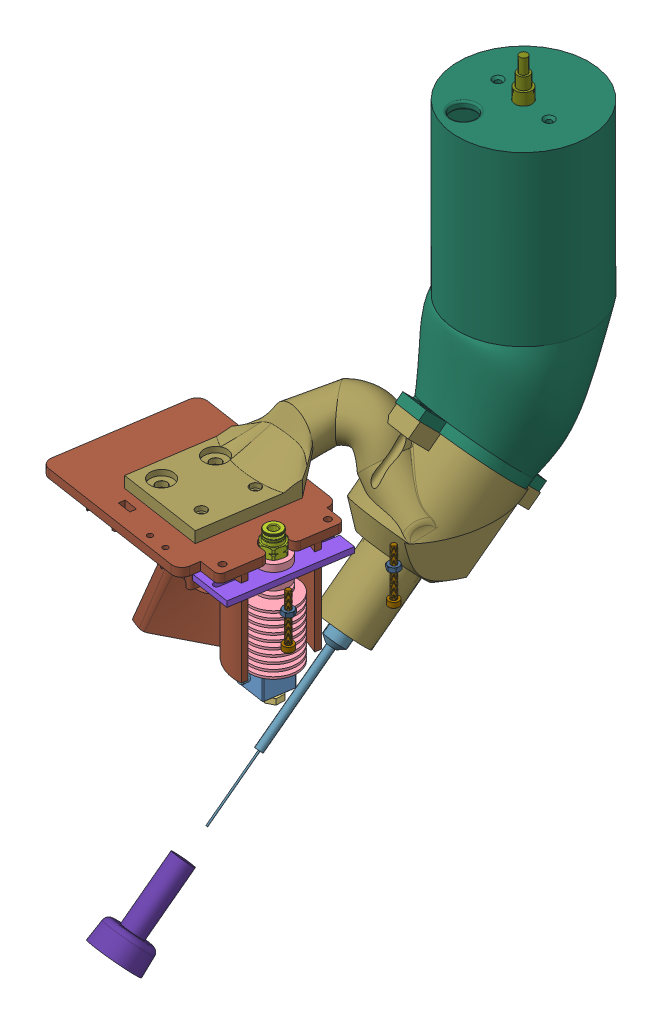
SolidWorks assembly new frame assembly, configuration Default. Lengths in mm.
Overall size (173.27 365.26 314.69).
20 component instances, 17 part files, 26 mates.
Components (placement in the parent):
- E3D-1: E3D [Default] at (19.6616 -17.5766 41.1358) x (-0.988808 0 -0.149195) z (0.149195 0 -0.988808) size (28.79 69.7 28.79)
  - E3D Heat Block-1: E3D Heat Block [Default] at origin size (16 12 16)
  - E3D Heatbreak-1: E3D Heatbreak [Default] at (-4 19.55 0) x (-0.93266 0 -0.360757) z (-0.360757 0 0.93266) size (6 25.1 6)
  - E3D Nozzle-1: E3D Nozzle [Default] at (-4 -3.5 0) x (-0.097107 0 -0.995274) z (0.995274 0 -0.097107) size (9.24 12.5 8)
  - E3D Heatsink-1: E3D Heatsink [1.75 Bowden] at (-4 39.15 0) x (0.986263 0 -0.165183) z (0.165183 0 0.986263) size (25 50.1 25)
  - cartridge heater-1: cartridge heater [Default] at (3 7 0) x (0 0 1) z (-0.150948 -0.988542 0) size (32 6.2 6.2)
  - thermistor-1: thermistor [Default] at (-6 2 6.5) x (-0.997586 0.069447 0) z (-0.069447 -0.997586 0) size (2 13.25 2)
- PB156_1_8-1: PB156_1_8 [Default] at (23.6169 46.9462 41.7325) x (0 -1 0) z (0.258692 0 0.96596) size (19.6 12.3 13.69)
- hotend bracket-1: hotend bracket [Default] at (30.0179 39.8834 73.0379) x (0.149195 0 -0.988808) z (0.988808 0 0.149195) size (60 3.04 22)
- socket head cap screw_am-14: socket head cap screw_am [B18.3.1M - 3 x 0.5 x 25 Hex SHCS -- 25SHX] at (70.4306 36.8834 24.1201) x (0 1 0) z (0 0 1) size (28 5.5 5.5)
- socket head cap screw_am-15: socket head cap screw_am [B18.3.1M - 3 x 0.5 x 25 Hex SHCS -- 25SHX] at (63.0246 36.8834 73.2045) x (0 1 0) z (-0.007083 0 0.999975) size (28 5.5 5.5)
- hex nut style 1_am-9: hex nut style 1_am [B18.2.4.1M - Hex nut, Style 1,  M3 x 0.5 --D-N] at (70.4306 55.9307 24.1201) x (1 0 0) z (0 1 0) size (5.5 6.35 2.4)
- hex nut style 1_am-10: hex nut style 1_am [B18.2.4.1M - Hex nut, Style 1,  M3 x 0.5 --D-N] at (63.0246 55.9307 73.2045) x (0.837169 0 0.546944) z (0 1 0) size (5.5 6.35 2.4)
- combined_frame-1: combined_frame [Default] at (-56.3869 -3.8922 -39.5735) x (0.988808 0 0.149195) z (-0.149195 0 0.988808) size (99.47 66.34 74.84)
- plasma_frame-1: plasma_frame [Default] at (-26.1139 51.1734 22.9932) x (-0.149195 0 0.988808) z (-0.988808 0 -0.149195) size (145.86 100.19 90.21)
- plasma_front_cone-1: plasma_front_cone [Default] at (59.1878 56.1232 -48.6716) x (-0.988808 0 -0.149195) z (-0.105497 0.707107 0.699193) size (47.33 150.21 106.88)
- needle_tip-1: needle_tip [Default] at (29.0488 10.8886 -7.4726) x (-0.903244 0.362246 0.230061) z (0.415958 0.607271 0.676906) size (11.1 112.62 11.1)
- plasma_frame_top-1: plasma_frame_top [Default] at (35.4811 55.4161 -50.1032) x (0.988808 0 0.149195) z (-0.105497 0.707107 0.699193) size (80.16 149.63 152.15)
- spark_gap-1: spark_gap [Default] at (39.4355 170.1901 -76.3116) size (41.3 55.93 42.1)
- cup_tip-1: cup_tip [Default] at (15.5523 -79.5738 81.9774) x (0.829341 -0.450523 -0.330489) z (-0.548693 -0.545003 -0.633961) size (25.35 46.03 25.35)
Mates (geometry in assembly coordinates):
- Concentric18: concentric aligned: cylinder of E3D-1/E3D Heatsink-1 through (23.6169 -3.4766 41.7325) axis (0 -1 0) radius 4.8641; cone of PB156_1_8-1 through (23.6169 46.9462 41.7325) axis (0 -1 0)
- Coincident8: coincident: circle of E3D-1/E3D Heatsink-1; cone of PB156_1_8-1 through (23.6169 47.4644 41.7325) axis (0 -1 0)
- Concentric38: concentric aligned: cylinder of E3D-1/E3D Heatsink-1 through (23.6169 -3.4766 41.7325) axis (0 -1 0) radius 6; cylinder of hotend bracket-1 through (23.6169 42.9234 41.7325) axis (0 -1 0) radius 6
- Coincident28: coincident anti-aligned: plane of E3D-1/E3D Heatsink-1 through (17.6177 42.9234 41.8297) normal (0 -1 0); plane of hotend bracket-1 through (23.6169 42.9234 41.7325) normal (0 1 0)
- Coincident30: coincident anti-aligned: plane of hotend bracket-1 through (23.6169 39.8834 41.7325) normal (0 -1 0); plane of socket head cap screw_am-15 through (60.2747 39.8834 73.185) normal (0 1 0)
- Coincident31: coincident anti-aligned: plane of hotend bracket-1 through (23.6169 39.8834 41.7325) normal (0 -1 0); plane of socket head cap screw_am-14 through (67.6806 39.8834 24.1201) normal (0 1 0)
- Concentric42: concentric anti-aligned: circle of socket head cap screw_am-14; circle of hex nut style 1_am-9
- Concentric58: concentric anti-aligned: circle of socket head cap screw_am-15; cylinder of hex nut style 1_am-10 through (63.0246 53.5307 73.2045) axis (0 1 0) radius 1.25
- Parallel2: parallel aligned: plane of E3D-1/E3D Heat Block-1 through (28.7657 -5.5766 34.4189) normal (0.988808 0 0.149195); plane of hotend bracket-1 through (30.0179 42.9234 73.0379) normal (0.988808 0 0.149195)
- Concentric59: concentric aligned: cylinder of E3D-1/E3D Heatsink-1 through (23.6169 -3.4766 41.7325) axis (0 -1 0) radius 8; cylinder of combined_frame-1 through (23.6169 51.1734 41.7325) axis (0 -1 0) radius 6.15
- Coincident34: coincident anti-aligned: plane of E3D-1/E3D Heatsink-1 through (18.7534 46.6234 41.8113) normal (0 1 0); plane of combined_frame-1 through (34.6864 46.6234 68.17) normal (0 -1 0)
- Parallel4: parallel aligned: plane of hotend bracket-1 through (30.0179 42.9234 73.0379) normal (0.988808 0 0.149195); plane of combined_frame-1 through (22.6196 46.6234 81.7213) normal (0.988808 0 0.149195)
- Concentric60: concentric anti-aligned: circle of combined_frame-1; cylinder of plasma_frame-1 through (-26.1139 57.1734 22.9932) axis (0 1 0) radius 6.12
- Concentric61: concentric anti-aligned: cylinder of combined_frame-1 through (-29.9035 46.6234 48.1089) axis (0 -1 0) radius 2.9; cylinder of plasma_frame-1 through (-29.9035 57.1734 48.1089) axis (0 1 0) radius 6.12
- Coincident35: coincident anti-aligned: plane of combined_frame-1 through (34.6864 51.1734 68.17) normal (0 1 0); plane of plasma_frame-1 through (-26.1139 51.1734 22.9932) normal (0 -1 0)
- Concentric64: concentric aligned: cylinder of plasma_frame-1 through (30.3118 19.3536 -15.8428) axis (-0.105497 -0.707107 0.699193) radius 19.5; cylinder of plasma_front_cone-1 through (30.4331 20.1666 -16.6467) axis (-0.105497 -0.707107 0.699193) radius 19.325
- Concentric65: concentric anti-aligned: circle of plasma_front_cone-1; cylinder of needle_tip-1 through (25.924 -10.0559 13.2375) axis (0.105497 0.707107 -0.699193) radius 5.55
- Concentric67: concentric: circle of plasma_frame-1; circle of plasma_frame_top-1
- Parallel5: parallel aligned: plane of combined_frame-1 through (34.6864 51.1734 68.17) normal (0 1 0); plane of plasma_front_cone-1 through (37.38 166.7298 -62.6887) normal (0 1 0)
- Coincident39: coincident aligned: plane of plasma_frame-1 through (30.3118 19.3536 -15.8428) normal (-0.105497 -0.707107 0.699193); plane of plasma_front_cone-1 through (40.5459 19.3536 -14.2986) normal (-0.105497 -0.707107 0.699193)
- Concentric68: concentric aligned: circle of plasma_frame_top-1; circle of spark_gap-1
- Coincident41: coincident anti-aligned: plane of plasma_frame_top-1 through (39.4355 201.5201 -76.3116) normal (0 -1 0); plane of spark_gap-1 through (43.4355 201.5201 -96.3616) normal (0 1 0)
- Concentric72: concentric: circle of plasma_frame-1; circle of plasma_frame_top-1
- Parallel6: parallel: plane of plasma_frame-1 through (37.9388 77.3364 -16.1222) normal (0.988808 0 0.149195); plane of plasma_frame_top-1 through (40.7872 76.6293 -35.0004) normal (0.988808 0 0.149195)
- Coincident42: coincident: plane of plasma_frame-1 through (35.5866 54.7089 -50.8024) normal (0.105497 0.707107 -0.699193); plane of plasma_frame_top-1 through (35.4811 55.4161 -50.1032) normal (-0.105497 -0.707107 0.699193)
- Concentric73: concentric anti-aligned: circle of plasma_front_cone-1; cylinder of cup_tip-1 through (12.0002 -103.3821 105.5192) axis (0.105497 0.707107 -0.699193) radius 5.6
